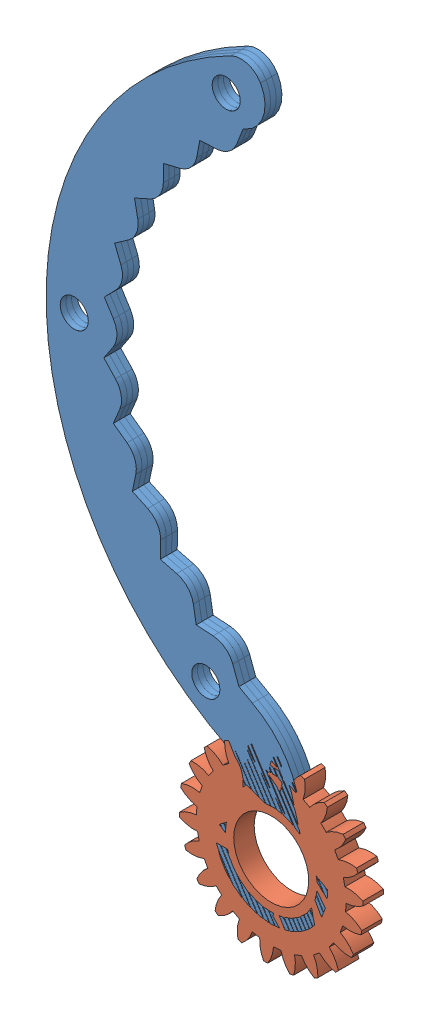
SolidWorks assembly dfsgd, configuration Default. Lengths in mm.
Overall size (30.55 70.75 1.82).
4 component instances, 2 part files, 9 mates.
Components (placement in the parent):
- kiskac1-1: kiskac1 [Varsayılan] at (65.4233 86.2581 103.6139) size (25 65.23 0.5)
- gear-3: gear [Default] at (35.7628 47.2729 101.9548) x (0 0 1) z (-0.933673 -0.358127 0) size (1.82 16.25 16.36)
- kiskac1-2: kiskac1 [Varsayılan] at (65.4233 86.2581 103.1139) size (25 65.23 0.5)
- kiskac1-3: kiskac1 [Varsayılan] at (65.4233 86.2581 102.6139) size (25 65.23 0.5)
Mates (geometry in assembly coordinates):
- Concentric2: concentric aligned: circle of gear-3; circle of kiskac1-1
- Coincident1: coincident aligned: plane of kiskac1-1 through (30.8288 101.4741 104.3639) normal (0 0 1); plane of gear-3 through (46.9247 41.0187 104.3639) normal (0 0 1)
- Coincident2: coincident anti-aligned: plane of kiskac1-1 through (30.8288 101.4741 103.8639) normal (0 0 -1); plane of kiskac1-2 through (30.8288 101.4741 103.8639) normal (0 0 1)
- Concentric3: concentric aligned: circle of kiskac1-1; circle of kiskac1-2
- Concentric4: concentric aligned: circle of kiskac1-1; circle of kiskac1-2
- Concentric5: concentric aligned: circle of kiskac1-1; circle of kiskac1-2
- Coincident5: coincident anti-aligned: plane of kiskac1-2 through (30.8288 101.4741 103.3639) normal (0 0 -1); plane of kiskac1-3 through (30.8288 101.4741 103.3639) normal (0 0 1)
- Concentric6: concentric aligned: circle of kiskac1-1; circle of kiskac1-3
- Concentric7: concentric aligned: circle of kiskac1-1; circle of kiskac1-3
